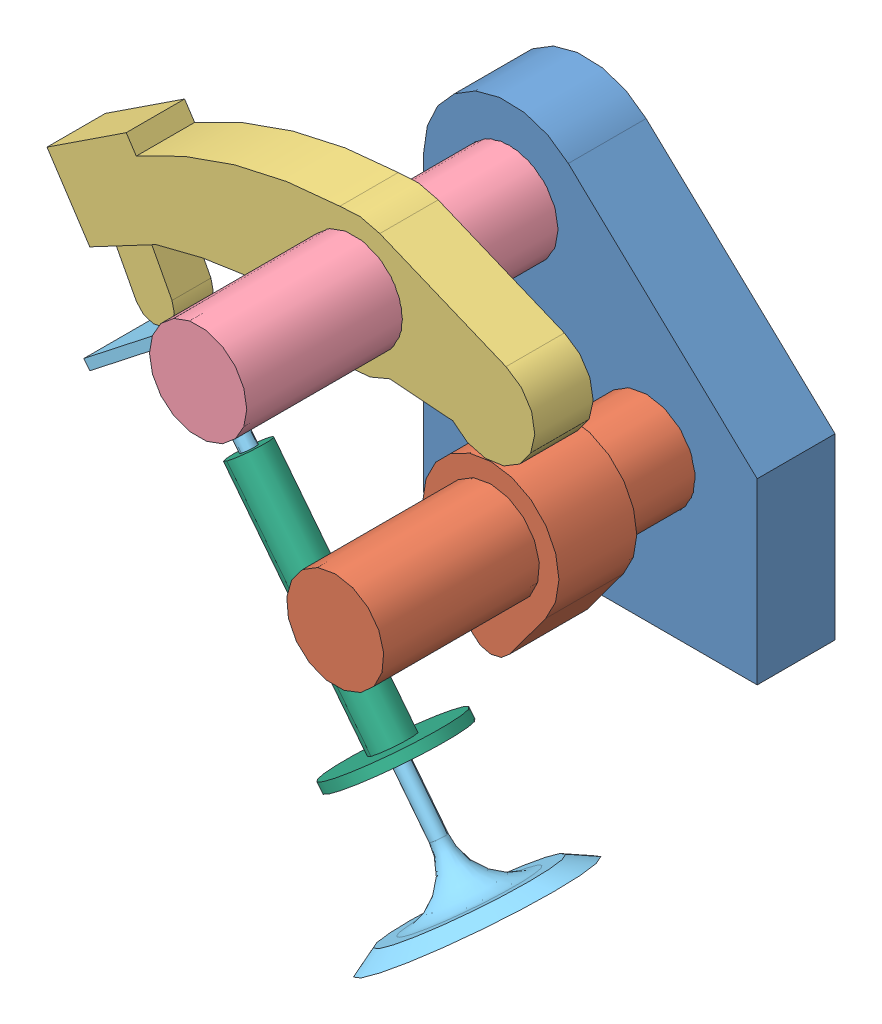
SolidWorks assembly valve_cam, configuration Default. Lengths in mm.
Overall size (78.71 94.62 50).
6 component instances, 6 part files, 11 mates.
Components (placement in the parent):
- shaft_mount-1: shaft_mount [Default] at (-11.2112 22.7057 0) x (1 0 0) z (0 0 -1) size (42.85 48.9 10)
- camshaft-1: camshaft [Default] at (68.4635 22.7057 -49.6471) x (1 0 0) z (0 -1 0) size (17.5 50 21.45)
- rocker-1: rocker [Default] at (62.0723 3.328 100.8971) x (0.97638 -0.216062 0) z (0.216062 0.97638 0) size (61.45 7.5 31.94)
- rocker_shaft-1: rocker_shaft [Default] at (68.3342 15.1769 99.6471) x (1 0 0) z (0 1 0) size (12.5 50 12.5)
- valve-1: valve [Default] at (-50.624 -50.0614 -48.5534) x (-0.452429 -0.8918 0) z (-0.8918 0.452429 0) size (46.19 25 64.83)
- valve_guide-1: valve_guide [Default] at (-6.2638 -23.6142 127.9335) x (0.666027 -0.014808 0.745781) z (-0.370256 0.861378 0.347763) size (22.54 15.45 32.68)
Mates (geometry in assembly coordinates):
- Coincident1: coincident anti-aligned: plane of shaft_mount-1 through (42.8483 0 10) normal (0 -1 0); plane of assembly through (0 0 0) normal (0 1 0)
- Coincident2: coincident: plane of assembly through (0 0 0) normal (1 0 0); plane of assembly; plane of shaft_mount-1 through (0 0 10) normal (-1 0 0)
- Coincident3: coincident anti-aligned: plane of shaft_mount-1 through (11.0102 37.892 0) normal (0 0 -1); plane of assembly through (0 0 0) normal (0 0 1)
- Concentric1: concentric aligned: cylinder of camshaft-1 through (28.6262 19.0012 20) axis (0 0 -1) radius 6.25; cylinder of shaft_mount-1 through (28.6262 19.0012 10) axis (0 0 -1) radius 6.25
- Coincident5: coincident aligned: plane of shaft_mount-1 through (11.0102 37.892 0) normal (0 0 -1); plane of camshaft-1 through (34.8762 19.0012 0) normal (0 0 -1)
- Concentric2: concentric anti-aligned: cylinder of shaft_mount-1 through (11.0102 37.892 10) axis (0 0 -1) radius 6.25; cylinder of rocker_shaft-1 through (11.0102 37.892 0) axis (0 0 1) radius 6.25
- Coincident6: coincident aligned: plane of camshaft-1 through (34.8762 19.0012 50) normal (0 0 1); plane of rocker_shaft-1 through (17.2602 37.892 50) normal (0 0 1)
- Concentric3: concentric aligned: cylinder of rocker-1 through (11.0102 37.892 22.5) axis (0 0 1) radius 6.25; cylinder of rocker_shaft-1 through (11.0102 37.892 0) axis (0 0 1) radius 6.25
- Coincident8: coincident aligned: plane of camshaft-1 through (21.5792 13.8144 30) normal (0 0 1); plane of rocker-1 through (30.5706 39.2792 30) normal (0 0 1)
- Concentric6: concentric aligned: cylinder of valve-1 through (-13.7829 19.5054 26.25) axis (0.617041 -0.786931 0) radius 0.96; cylinder of valve_guide-1 through (-6.218 9.8577 26.25) axis (0.617041 -0.786931 0) radius 0.96
- Parallel1: parallel anti-aligned: plane of rocker-1 through (-16.6166 29.6517 28.75) normal (0 0 1); plane of valve-1 through (-24.3908 12.7761 21.25) normal (0 0 -1)
